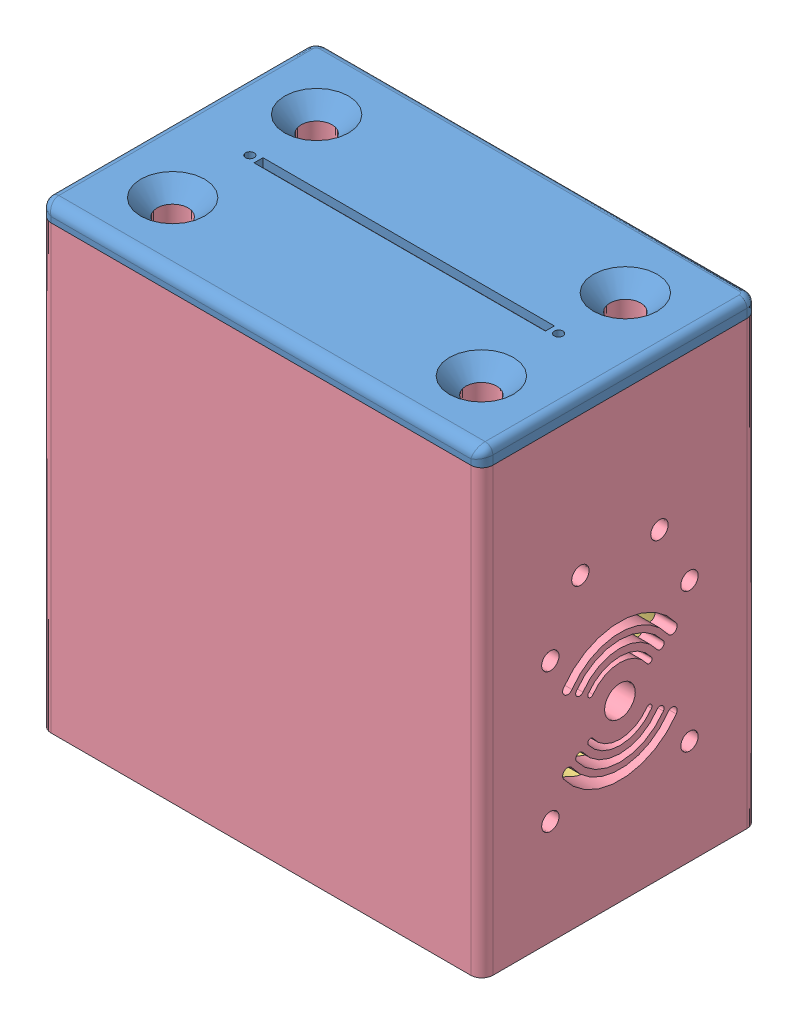
SolidWorks assembly Motor_Controller_Assembly, configuration Default. Lengths in mm.
Overall size (101.6 105.41 63.5).
7 component instances, 7 part files, 13 mates.
Components (placement in the parent):
- Motor_Controller_Box_Lid-1: Motor_Controller_Box_Lid [Default] at (96.52 101.6 103.1) size (101.6 5.81 63.5)
- AAA_Battery_Holder-1: AAA_Battery_Holder [Default] at (15.0758 5.08 58.42) x (0 0 -1) z (1 0 0) size (11.5 51.8 48.5)
- 40mm_Fan v1-1: 40mm_Fan v1 [Default] at (71.44 20.0433 13.25) x (0 -1 0) z (0 0 1) size (40 20 40)
- Motor_Controller_Box-1: Motor_Controller_Box [Default] at (-5.08 0 1.5) size (101.6 101.6 63.5)
- Strain_Relief_Main_Battery-1: Strain_Relief_Main_Battery [Default] at (0 63.1 15.2475) x (0 0 -1) z (1 0 0) size (36 6.5 30)
- Talon_Victor-1: Talon_Victor [Default] at (35 29.58 22.08) x (1 0 0) z (0 -1 0) size (70 28.5 49)
- Strain_Relief_Talon_Output-2: Strain_Relief_Talon_Output [Default] at (91.44 64.6 48.2475) x (0 0 1) z (-1 0 0) size (30 5 30)
Mates (geometry in assembly coordinates):
- Coincident1: coincident anti-aligned: plane of Motor_Controller_Box_Lid-1 through (96.52 101.6 103.1) normal (0 -1 0); plane of Motor_Controller_Box-1 through (-5.08 101.6 1.5) normal (0 1 0)
- Coincident2: coincident aligned: plane of Motor_Controller_Box_Lid-1 through (96.52 105.41 65) normal (0 0 1); plane of Motor_Controller_Box-1 through (-5.08 101.6 65) normal (0 0 1)
- Coincident3: coincident aligned: plane of Motor_Controller_Box_Lid-1 through (-5.08 105.41 65) normal (-1 0 0); plane of Motor_Controller_Box-1 through (-5.08 101.6 1.5) normal (-1 0 0)
- Coincident4: coincident anti-aligned: plane of Motor_Controller_Box-1 through (0 101.6 1.5) normal (1 0 0); plane of Strain_Relief_Main_Battery-1 through (0 69.6 15.2475) normal (-1 0 0)
- Concentric1: concentric: cylinder of Motor_Controller_Box-1 through (4.92 69.6 22.66) axis (-1 0 0) radius 4; point of Strain_Relief_Main_Battery-1
- Coincident8: coincident anti-aligned: plane of 40mm_Fan v1-1 through (91.44 20.0433 13.25) normal (1 0 0); plane of Motor_Controller_Box-1 through (91.44 81.6 33.1806) normal (-1 0 0)
- Concentric2: concentric aligned: cylinder of 40mm_Fan v1-1 through (19.1141 40.0433 33.25) axis (1 0 0) radius 18.5; circle of Motor_Controller_Box-1
- Coincident11: coincident anti-aligned: plane of Motor_Controller_Box-1 through (-5.08 101.6 6.58) normal (0 0 1); plane of Talon_Victor-1 through (35 29.58 6.58) normal (0 0 -1)
- Coincident12: coincident anti-aligned: plane of Motor_Controller_Box-1 through (-5.08 5.08 1.5) normal (0 1 0); plane of Talon_Victor-1 through (70 5.08 6.58) normal (0 -1 0)
- Coincident13: coincident anti-aligned: plane of Motor_Controller_Box-1 through (0 101.6 1.5) normal (1 0 0); plane of Talon_Victor-1 through (0 54.08 6.58) normal (-1 0 0)
- Parallel2: parallel anti-aligned: cylinder of Motor_Controller_Box-1 through (86.52 69.6 42.34) axis (1 0 0) radius 2; face of Strain_Relief_Talon_Output-2
- Coincident15: coincident anti-aligned: plane of Motor_Controller_Box-1 through (91.44 81.6 33.1806) normal (-1 0 0); plane of Strain_Relief_Talon_Output-2 through (91.44 69.6 48.2475) normal (1 0 0)
- Concentric5: concentric: point of Strain_Relief_Talon_Output-2; cylinder of Motor_Controller_Box-1 through (86.52 69.6 24.16) axis (1 0 0) radius 2
